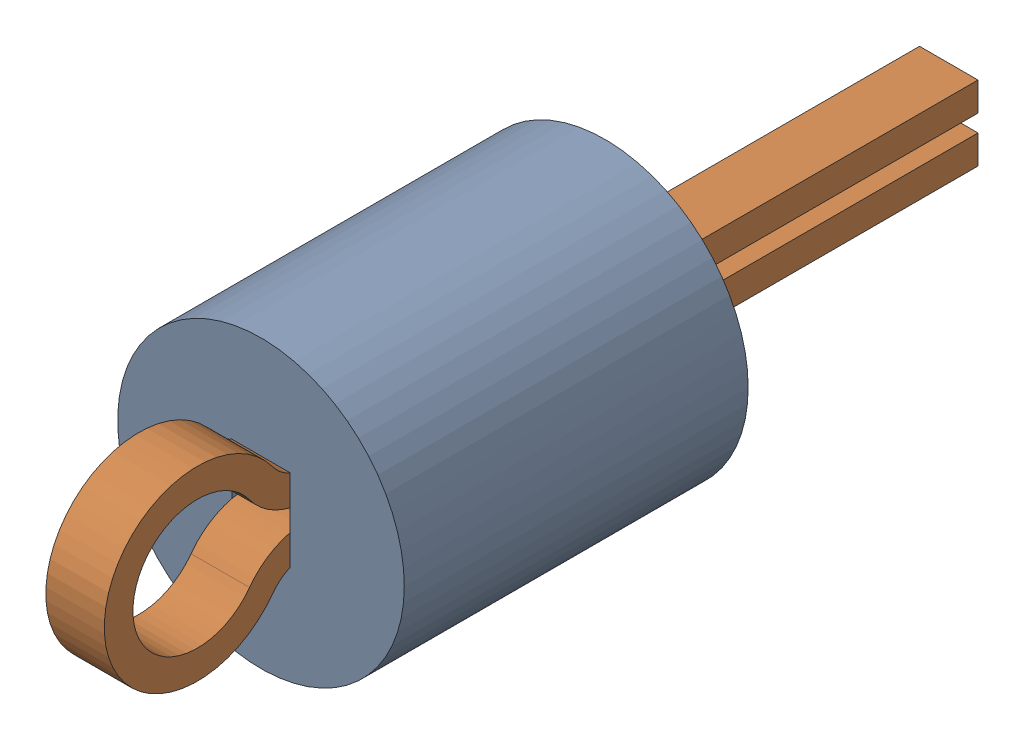
SolidWorks assembly TP8, configuration Default. Lengths in mm.
Overall size (2.5 2.5 7.62).
3 component instances, 2 part files, 0 mates.
Components (placement in the parent):
- Keystone_5002-1: Keystone_5002 [Default] at (30.9835 31.7529 0) size (2.5 2.5 7.62)
  - Keystone5002_white-1: Keystone5002_white [Default] at origin size (2.5 2.5 3)
  - Keystone500x_wire-1: Keystone500x_wire [Default] at origin size (0.51 1.62 7.62)
